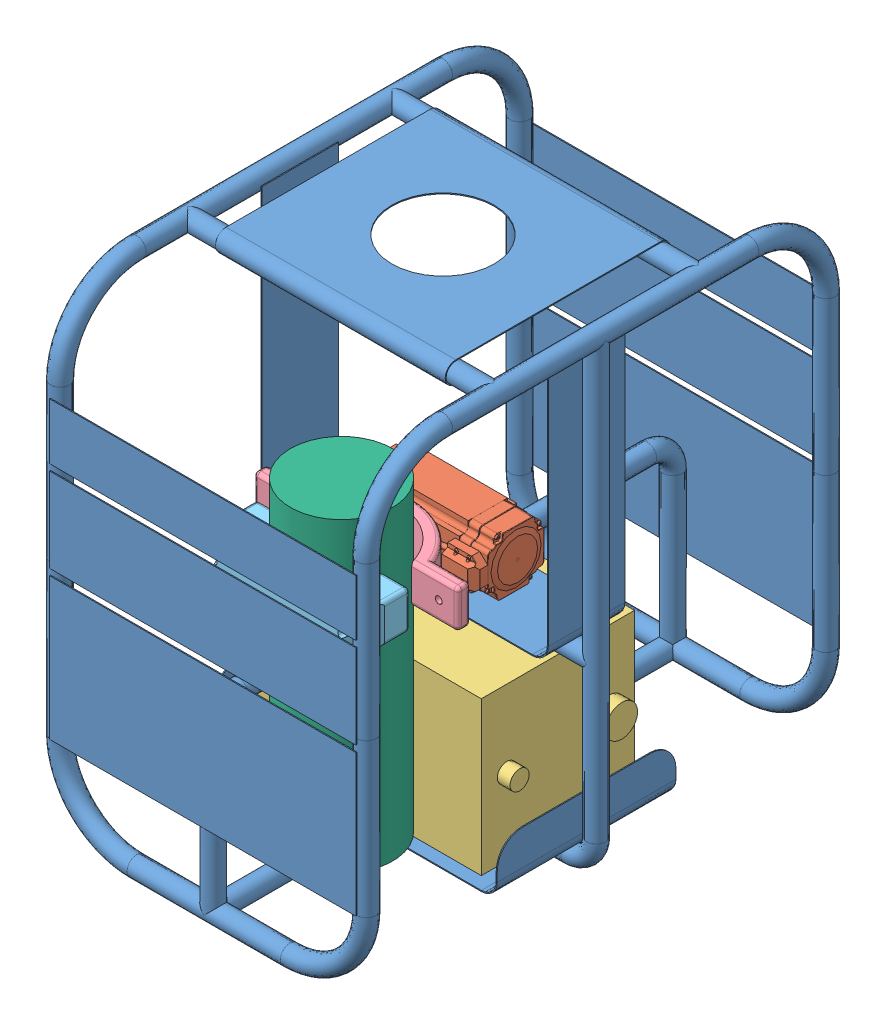
SolidWorks assembly Chassis With Components, configuration Default. Lengths in mm.
Overall size (336.91 477.27 484.81).
6 component instances, 6 part files, 8 mates.
Components (placement in the parent):
- Rope Robot Chassis Master-1: Rope Robot Chassis Master [Default] at (149.1739 277.2276 363.839) size (323.85 477.27 478.28)
- 23HS45-4204D-E1000-MC (1)-1: 23HS45-4204D-E1000-MC (1) [Default] at (196.4239 264.9686 355.3921) x (0 1 0) z (-1 0 0) size (57.01 145.68 152.5)
- battery-1: battery [Default] at (149.1739 59.1686 363.839) size (241.3 152.4 152.4)
- Bottom_Piece_2-1: Bottom_Piece_2 [Default] at (222.5541 359.4327 538.21) x (1 0 0) z (0 -1 0) size (203.2 56.12 38.55)
- Frame_Side_Piece_2-1: Frame_Side_Piece_2 [Default] at (165.4569 378.1667 532.2825) x (1 0 0) z (0 -1 0) size (152.4 55.88 88.9)
- pvc-1: pvc [Default] at (222.5541 278.0123 538.21) x (0 1 0) z (-0.615053 0 0.788486) size (304.8 101.6 101.6)
Mates (geometry in assembly coordinates):
- Coincident3: coincident anti-aligned: plane of Rope Robot Chassis Master-1 through (22.1739 236.9686 325.739) normal (0 1 0); plane of 23HS45-4204D-E1000-MC (1)-1 through (117.2279 236.9686 327.3921) normal (0 -1 0)
- Coincident4: coincident anti-aligned: plane of Rope Robot Chassis Master-1 through (22.1739 59.1686 452.739) normal (0 1 0); plane of battery-1 through (149.1739 59.1686 363.839) normal (0 -1 0)
- Width4: width anti-aligned: plane of battery-1 through (263.4739 211.5686 440.039) normal (1 0 0); plane of Rope Robot Chassis Master-1 through (34.8739 211.5686 440.039) normal (-1 0 0); plane of battery-1 through (291.0329 74.0276 452.739) normal (-1 0 0); plane of Rope Robot Chassis Master-1 through (7.3149 108.9526 452.739) normal (1 0 0)
- Width5: width anti-aligned: plane of battery-1 through (34.8739 211.5686 287.639) normal (0 0 -1); plane of Rope Robot Chassis Master-1 through (34.8739 211.5686 440.039) normal (0 0 1); plane of battery-1 through (22.1739 74.0276 452.739) normal (0 0 1); plane of Rope Robot Chassis Master-1 through (22.1739 74.0276 274.939) normal (0 0 -1)
- Coincident5: coincident anti-aligned: plane of Rope Robot Chassis Master-1 through (149.1739 277.2276 601.964) normal (0 0 -1); plane of Frame_Side_Piece_2-1 through (286.0541 340.0667 601.964) normal (0 0 1)
- Concentric1: concentric anti-aligned: cylinder of Frame_Side_Piece_2-1 through (222.5541 340.0667 538.21) axis (0 1 0) radius 51.054; cylinder of pvc-1 through (222.5541 430.4123 538.21) axis (0 -1 0) radius 50.8
- Concentric2: concentric anti-aligned: cylinder of Bottom_Piece_2-1 through (222.5541 340.3827 538.21) axis (0 1 0) radius 57.404; cylinder of pvc-1 through (222.5541 430.4123 538.21) axis (0 -1 0) radius 50.8
- Parallel1: parallel anti-aligned: plane of Bottom_Piece_2-1 through (278.1679 340.3827 523.986) normal (0 0 1); plane of Frame_Side_Piece_2-1 through (298.7541 340.0667 546.084) normal (0 0 -1)
